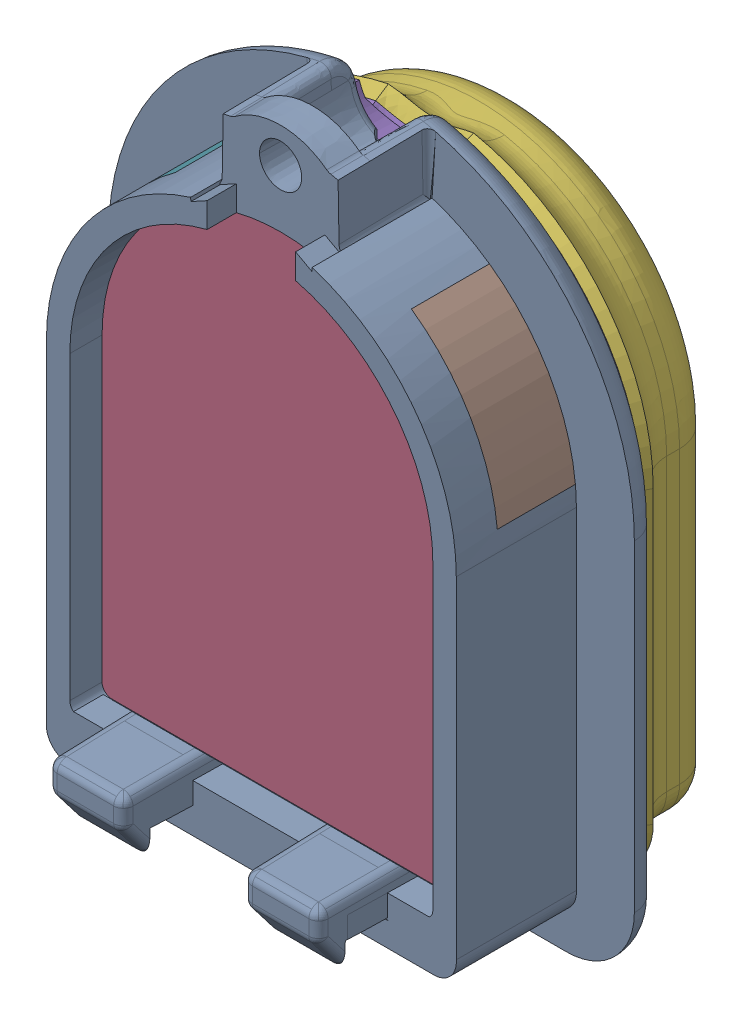
SolidWorks assembly OriginalDesign, configuration 默认. Lengths in mm.
Overall size (26.95 34.26 17.16).
7 component instances, 6 part files, 18 mates.
Components (placement in the parent):
- OriginalTip1-1: OriginalTip1 [默认] at (-1.9035 7.7463 -5.5591) size (26.95 34.26 11.2)
- Originallensnew-1: Originallensnew [默认] at (-1.9035 7.7463 -5.5591) size (18.6 25.2 6)
- OriginalSkin0.2-1: OriginalSkin0.2 [默认] at (-1.9035 7.4963 -5.5591) x (-1 0 0) z (0 0 -1) size (23.9 30.06 5.2)
- OriginalSkin1-1: OriginalSkin1 [默认] at (-1.9035 7.4963 -5.5591) x (-1 0 0) z (0 0 -1) size (22.77 29.32 5.25)
- Originalsidelens1-1: Originalsidelens1 [默认] at (-1.9035 7.7463 -6.2091) size (6.4 7.71 4)
- Originalsidelens1-2: Originalsidelens1 [默认] at (-1.9035 7.7463 2.0909) x (-1 0 0) z (0 0 -1) size (6.4 7.71 4)
- Originalbottomlens-1: Originalbottomlens [默认] at (-5.9035 -10.5037 0.4409) x (1 0 0) z (0 1 0) size (8 4.5 2.35)
Mates (geometry in assembly coordinates):
- 同心1: concentric aligned: cylinder of Tip1-1 through (-1.9035 7.7463 51.2878) axis (0 0 -1) radius 9.3; cylinder of lensnew-1 through (-1.9035 7.7463 0.4409) axis (0 0 -1) radius 9.3
- 重合1: coincident anti-aligned: plane of Tip1-1 through (-1.9035 -8.1537 51.2878) normal (0 1 0); plane of lensnew-1 through (-11.2035 -8.1537 0.4409) normal (0 -1 0)
- 重合2: coincident aligned: plane of Tip1-1 through (-1.964 4.3089 -5.5591) normal (0 0 -1); plane of lensnew-1 through (-1.9035 7.7463 -5.5591) normal (0 0 -1)
- 重合3: coincident anti-aligned: plane of lensnew-1 through (-1.9035 7.7463 -5.5591) normal (0 0 -1); plane of Skin0.2-1 through (-1.9035 7.4963 -5.5591) normal (0 0 1)
- 同心2: concentric aligned: cone of Tip1-1 through (-1.9035 19.9963 -1.0591) axis (0 0 1); cylinder of Skin0.2-1 through (-1.9035 19.9963 -6.3091) axis (0 0 1) radius 2.75
- 宽度1: width aligned: plane of Skin0.2-1 through (-13.8535 7.4963 -5.5591) normal (-1 0 0); plane of Tip1-1 through (10.0465 7.4963 -5.5591) normal (1 0 0); plane of Skin0.2-1 through (-12.4035 7.7463 2.0909) normal (-1 0 0); plane of Tip1-1 through (8.5965 7.7463 2.0909) normal (1 0 0)
- 重合4: coincident anti-aligned: plane of Skin0.2-1 through (-1.9035 7.4963 -10.7591) normal (0 0 -1); plane of Skin1-1 through (-1.9035 7.4963 -10.7591) normal (0 0 1)
- 宽度2: width anti-aligned: plane of Skin0.2-1 through (-13.8535 7.4963 -5.5591) normal (-1 0 0); plane of Skin1-1 through (10.0465 7.4963 -5.5591) normal (1 0 0); plane of Skin0.2-1 through (-12.8325 0.0508 -6.2245) normal (-0.891007 0 0.45399); plane of Skin1-1 through (9.0255 0.0508 -6.2245) normal (0.891007 0 0.45399)
- 重合5: coincident aligned: cone of Skin0.2-1 through (-1.9035 7.4963 -6.2245) axis (0 0 1); cone of Skin1-1 through (-1.9035 7.4963 -6.2245) axis (0 0 1)
- 重合6: coincident anti-aligned: plane of Tip1-1 through (-16.7251 9.2061 -4.0591) normal (0.104528 0.994522 0); plane of sidelens1-1 through (8.4147 6.5638 -0.0591) normal (-0.104528 -0.994522 0)
- 重合7: coincident anti-aligned: plane of Tip1-1 through (-1.9035 7.7463 -4.0591) normal (0 0 1); plane of sidelens1-1 through (8.4147 6.5638 -4.0591) normal (0 0 -1)
- 同心3: concentric aligned: cylinder of Tip1-1 through (-1.9035 7.7463 2.0909) axis (0 0 -1) radius 10.5; cylinder of sidelens1-1 through (-1.9035 7.7463 -0.0591) axis (0 0 -1) radius 10.5
- 同心4: concentric anti-aligned: cylinder of Tip1-1 through (-1.9035 7.7463 2.0909) axis (0 0 -1) radius 10.5; cylinder of sidelens1-2 through (-1.9035 7.7463 -4.0591) axis (0 0 1) radius 10.5
- 重合8: coincident anti-aligned: plane of Tip1-1 through (12.0819 17.1622 -0.0591) normal (0.104528 -0.994522 0); plane of sidelens1-2 through (-13.0579 14.5199 -4.0591) normal (-0.104528 0.994522 0)
- 重合9: coincident anti-aligned: plane of Tip1-1 through (-1.9035 7.7463 -4.0591) normal (0 0 1); plane of sidelens1-2 through (-1.9035 7.7463 -4.0591) normal (0 0 -1)
- 重合10: coincident anti-aligned: plane of lensnew-1 through (-11.2035 -8.1537 0.4409) normal (0 -1 0); plane of bottomlens-1 through (-5.9035 -8.1537 0.4409) normal (0 1 0)
- 重合11: coincident anti-aligned: plane of Tip1-1 through (-5.9035 -18.1537 0.4409) normal (0 0 -1); plane of bottomlens-1 through (-5.9035 -8.1537 0.4409) normal (0 0 1)
- 重合12: coincident anti-aligned: plane of Tip1-1 through (2.0965 -18.1537 0.4409) normal (-1 0 0); plane of bottomlens-1 through (2.0965 -8.1537 0.4409) normal (1 0 0)
